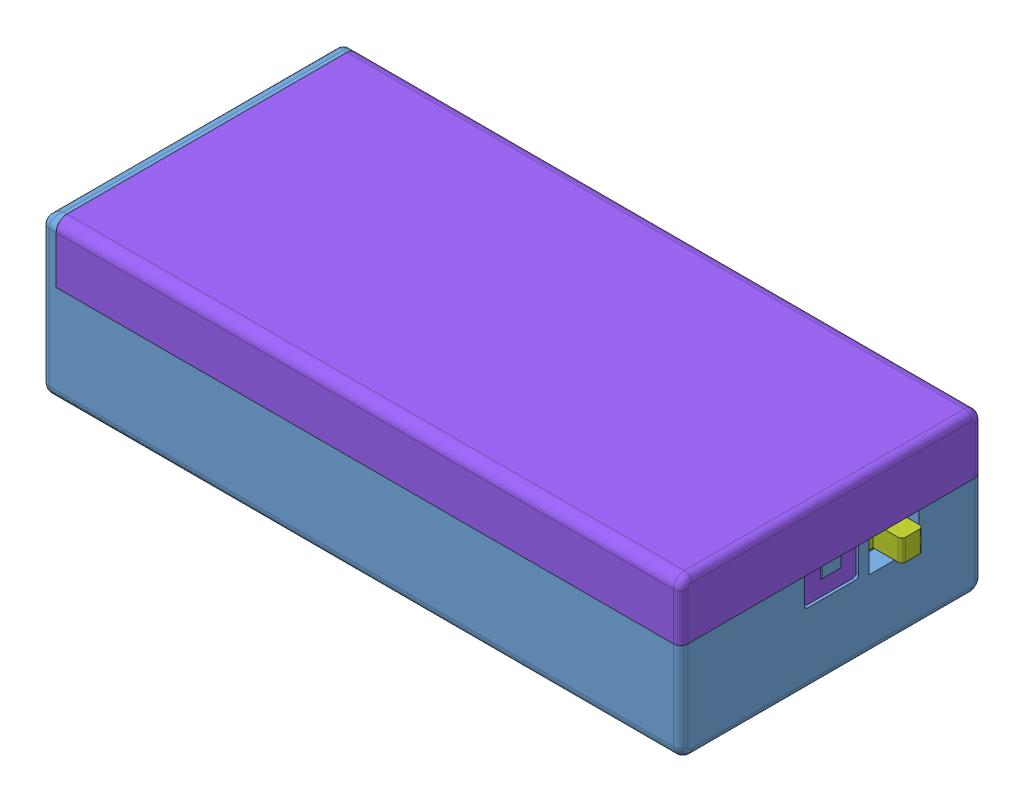
SolidWorks assembly Assem1, configuration Default. Lengths in mm.
Overall size (90.8 22 42.01).
10 component instances, 8 part files, 0 mates.
Components (placement in the parent):
- 3.7V 2X 18650 BATTERY HOLDER WITH ON OFF SWITCH v1.step-1: 3.7V 2X 18650 BATTERY HOLDER WITH ON OFF SWITCH v1.step [Default] at origin size (90.8 22 42.01)
  - CASE, 3.7V 2X 18650 BATTERY HOLDER WITH ON OFF SWITCH.step-1: CASE, 3.7V 2X 18650 BATTERY HOLDER WITH ON OFF SWITCH.step [Default] at origin size (89 22 42.01)
  - SWITCH AND WIRING COVER, 3.7V 2X 18650 BATTERY HOLDER WITH ON OFF SWITCH.step-1: SWITCH AND WIRING COVER, 3.7V 2X 18650 BATTERY HOLDER WITH ON OFF SWITCH.step [Default] at (35.95 15 0) x (1 0 0) z (0 0 -1) size (11.3 3.7 38)
  - BATTERY CONDUCTION CLIP, 3.7V 2X 18650 BATTERY HOLDER WITH ON OFF SWITCH.step-1: BATTERY CONDUCTION CLIP, 3.7V 2X 18650 BATTERY HOLDER WITH ON OFF SWITCH.step [Default] at (-42.5 8.2 0) x (0 0 1) z (0 1 0) size (37 2.6 14)
  - SPRING, 3.7V 2X 18650 BATTERY HOLDER WITH ON OFF SWITCH.step-1: SPRING, 3.7V 2X 18650 BATTERY HOLDER WITH ON OFF SWITCH.step [Default] at (-37.0934 10.6 -9.5) x (0 0 -1) z (0 -1 0) size (7.33 10.2 7.44)
  - BATTERY CONDUCTION CLIP, POSITIVE TERMINAL, 3.7V 2X 18650 BATTERY HOLDER WITH ON OFF SWITCH.step-1: BATTERY CONDUCTION CLIP, POSITIVE TERMINAL, 3.7V 2X 18650 BATTERY HOLDER WITH ON OFF SWITCH.step [Default] at (30.1 7.7 -9.75) x (0 0 -1) z (0 1 0) size (15 6.6 13)
  - BATTERY CONDUCTION CLIP, NEGATIVE TERMINAL, 3.7V 2X 18650 BATTERY HOLDER WITH ON OFF SWITCH.step-1: BATTERY CONDUCTION CLIP, NEGATIVE TERMINAL, 3.7V 2X 18650 BATTERY HOLDER WITH ON OFF SWITCH.step [Default] at (30.1 7.7 9.75) x (0 0 -1) z (0 1 0) size (15 5.6 13)
  - SPRING, 3.7V 2X 18650 BATTERY HOLDER WITH ON OFF SWITCH.step-2: SPRING, 3.7V 2X 18650 BATTERY HOLDER WITH ON OFF SWITCH.step [Default] at (24.6934 9.6 9.75) x (0 0 -1) z (0 1 0) size (7.33 10.2 7.44)
  - SLIDE SWITCH SPDT, 3.7V 2X 18650 BATTERY HOLDER WITH ON OFF SWITCH_OFF.step-1: SLIDE SWITCH SPDT, 3.7V 2X 18650 BATTERY HOLDER WITH ON OFF SWITCH_OFF.step [Default] at (36.7 11.3 -8.7) x (0 0 -1) z (0 -1 0) size (19 12 6)
  - COVER, 3.7V 2X 18650 BATTERY HOLDER WITH ON OFF SWITCH.step-1: COVER, 3.7V 2X 18650 BATTERY HOLDER WITH ON OFF SWITCH.step [Default] at (1 22 0) x (1 0 0) z (0 0 -1) size (89.6 11.9 42)
